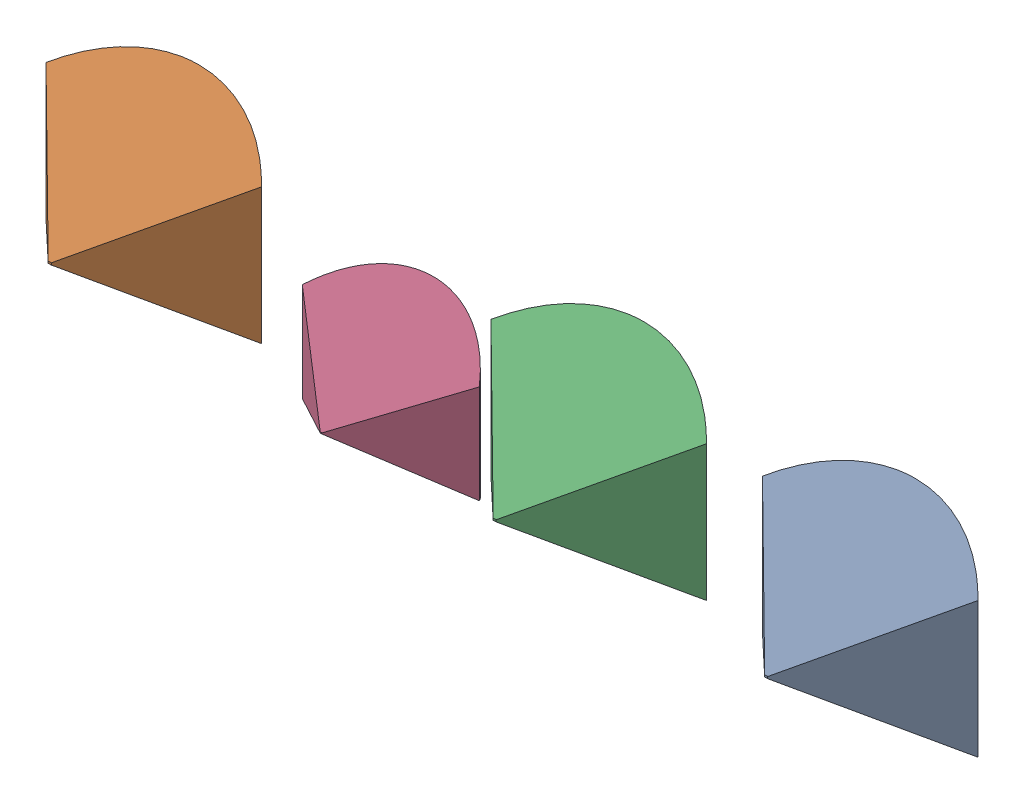
SolidWorks assembly AM0600115_REV01_ASM_EXTERNA-255_ASM, configuration AM0600115_REV01_ASM_EXTERNA-255_ASM. Lengths in mm.
Overall size (123.6 25.75 21.32).
7 component instances, 2 part files, 0 mates.
Components (placement in the parent):
- LEN000021_WITH_FOV_ASM_1_ASM_1__ASM-1: LEN000021_WITH_FOV_ASM_1_ASM_1__ASM [LEN000021_WITH_FOV_ASM_1_ASM_1__ASM] at (58.8 0 -0.82) x (-1 0 0) z (0 0 -1) size (28.6 25.75 19.81)
  - DS8480D-ASSM-MECH_00D1_OP_D6__1-1: DS8480D-ASSM-MECH_00D1_OP_D6__1 [DS8480D-ASSM-MECH_00D1_OP_D6__1] at (0 0 0.65) size (28.6 25.75 19.81)
- LEN000021_WITH_FOV_ASM_1_ASM_1__ASM-2: LEN000021_WITH_FOV_ASM_1_ASM_1__ASM [LEN000021_WITH_FOV_ASM_1_ASM_1__ASM] at (-36.2 0 -0.82) x (-1 0 0) z (0 0 -1) size (28.6 25.75 19.81)
  - DS8480D-ASSM-MECH_00D1_OP_D6__1-1: DS8480D-ASSM-MECH_00D1_OP_D6__1 [DS8480D-ASSM-MECH_00D1_OP_D6__1] at (0 0 0.65) size (28.6 25.75 19.81)
- LEN000021_WITH_FOV_ASM_1_ASM_1__ASM-3: LEN000021_WITH_FOV_ASM_1_ASM_1__ASM [LEN000021_WITH_FOV_ASM_1_ASM_1__ASM] at (22.8 0 -0.82) x (-1 0 0) z (0 0 -1) size (28.6 25.75 19.81)
  - DS8480D-ASSM-MECH_00D1_OP_D6__1-1: DS8480D-ASSM-MECH_00D1_OP_D6__1 [DS8480D-ASSM-MECH_00D1_OP_D6__1] at (0 0 0.65) size (28.6 25.75 19.81)
- DS8580B-ASSM-MECH_02_OP_D6__FOV-1: DS8580B-ASSM-MECH_02_OP_D6__FOV [DS8580B-ASSM-MECH_02_OP_D6__FOV] at (1.3 0 -1.31) x (-1 0 0) z (0 0 -1) size (23.49 21.02 14.9)
